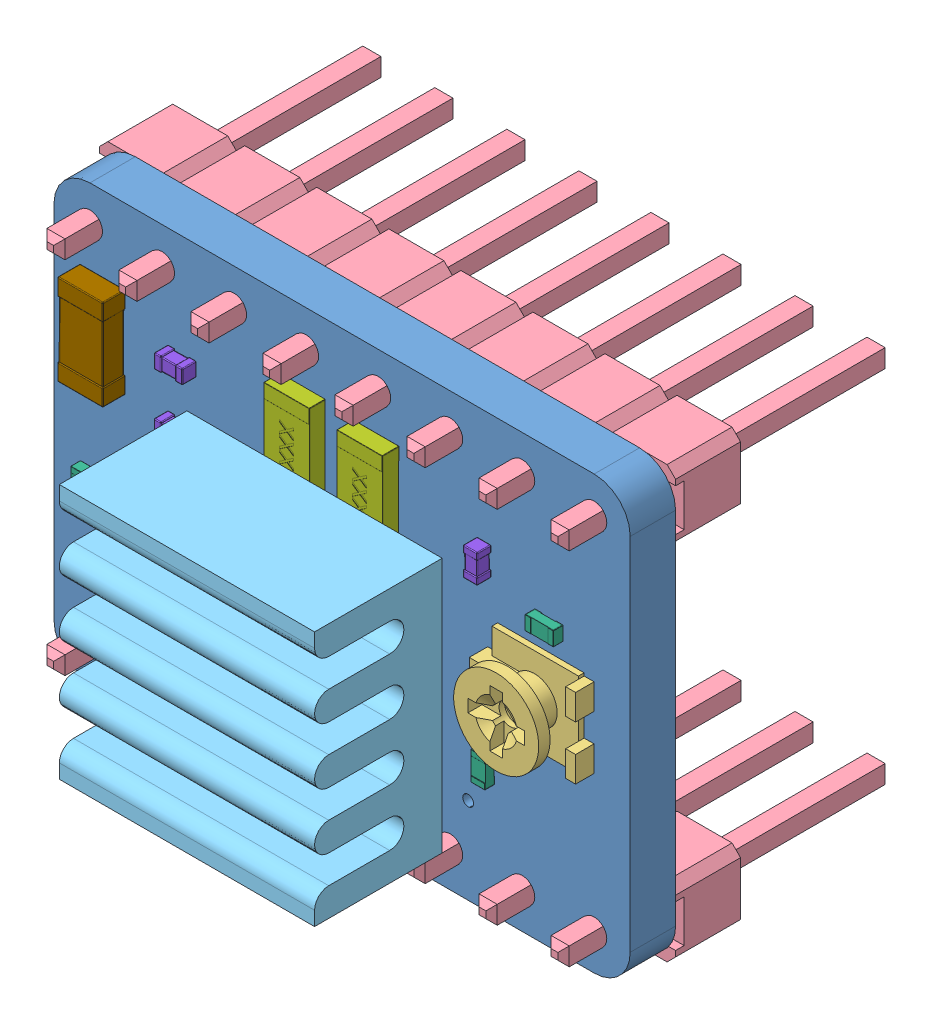
SolidWorks assembly stepstick, configuration Défaut. Lengths in mm.
Overall size (20.32 15.24 15.96).
19 component instances, 9 part files, 0 mates.
Components (placement in the parent):
- stepstick-1: stepstick [Défaut] at origin size (20.32 15.24 1.6)
- QFN28ET_A4983-1: QFN28ET_A4983 [Défaut] at (60.96 57.15 1.6) size (5 5 0.9)
- TRIMPOT3MM_TRIMPOTSMD-1: TRIMPOT3MM_TRIMPOTSMD [Défaut] at (67.945 58.293 1.6) x (0 1 0) z (0 0 1) size (3 3.75 1.55)
- Pin header pitch 2.54mm_08 contacts-1: Pin header pitch 2.54mm_08 contacts [Défaut] at (69.85 52.07 -2.29) x (-1 0 0) z (0 0 -1) size (20.32 2.49 11.54)
- Pin header pitch 2.54mm_08 contacts-2: Pin header pitch 2.54mm_08 contacts [Défaut] at (69.85 64.77 -2.29) x (-1 0 0) z (0 0 -1) size (20.32 2.49 11.54)
- Heatsink For A4988-1: Heatsink For A4988 [Défaut] at (61.3133 57.6122 2.4232) x (0 1 0) z (1 0 0) size (9 5 9)
- R0402-01-1: R0402-01 [Défaut] at (68.2722 60.6475 1.6131) x (1 0 0) z (0 -1 0) size (1 0.35 0.5)
- R0402-01-2: R0402-01 [Défaut] at (66.0925 55.3045 1.5976) x (0 -1 0) z (-1 0 0) size (1 0.35 0.5)
- R0402-01-3: R0402-01 [Défaut] at (63.5962 53.8945 1.5922) x (-1 0 0) z (0 1 0) size (1 0.35 0.5)
- R1206-01-1: R1206-01 [Défaut] at (62.3168 62.0471 1.7448) x (0 -1 0) z (-1 0 0) size (3.1 0.6 1.6)
- R1206-01-2: R1206-01 [Défaut] at (59.5663 62.032 1.5671) x (0 -1 0) z (-1 0 0) size (3.1 0.6 1.6)
- R0402-01-4: R0402-01 [Défaut] at (52.1553 57.0656 1.7677) x (0 -1 0) z (-1 0 0) size (1 0.35 0.5)
- C0402-1: C0402 [Défaut] at (57.1293 54.2576 1.8326) size (1 0.57 0.56)
- C0402-2: C0402 [Défaut] at (54.5698 55.4202 1.8561) size (1 0.57 0.56)
- C0402-3: C0402 [Défaut] at (65.7234 61.5632 1.8516) x (0 -1 0) z (0 0 1) size (1 0.57 0.56)
- C0402-4: C0402 [Défaut] at (55.3576 60.0066 1.8835) size (1 0.57 0.56)
- C0402-5: C0402 [Défaut] at (56.5915 56.9455 1.8091) x (0 -1 0) z (0 0 1) size (1 0.57 0.56)
- C0402-6: C0402 [Défaut] at (55.3483 62.0044 1.8729) size (1 0.57 0.56)
- C1206B-1: C1206B [Défaut] at (52.5232 61.8008 1.6006) x (0 -1 0) z (-1 0 0) size (3.2 0.87 1.66)
